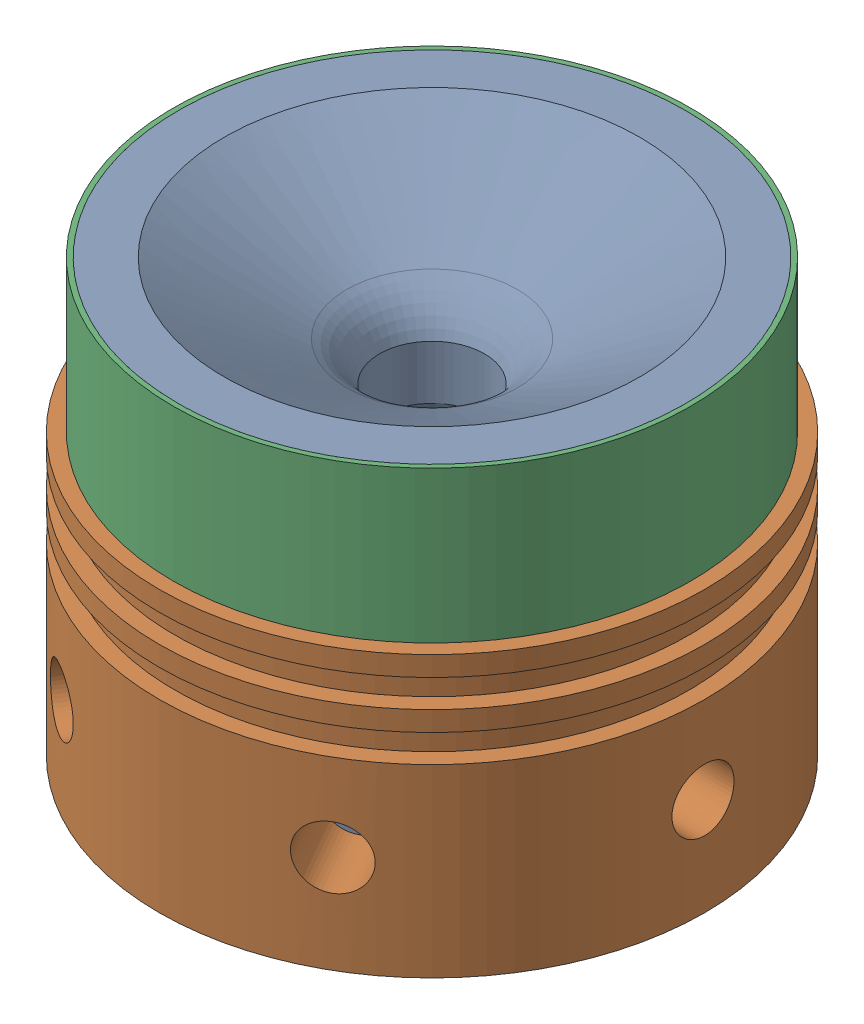
SolidWorks assembly 01_Nozzle_Assembly_COTS_GOW75BSTR23_V2.0, configuration Default. Lengths in mm.
Overall size (69.8 55.21 69.8).
3 component instances, 3 part files, 4 mates.
Components (placement in the parent):
- COTS_Nozzle_Modified_GOW75BSTR23_V1.0-1: COTS_Nozzle_Modified_GOW75BSTR23_V1.0 [Default] at (-2.3642 17.5716 -4.7601) size (64.95 55.21 64.95)
- Nozzle_Retainer_COTS_GOW75BSTR23_V2.0-1: Nozzle_Retainer_COTS_GOW75BSTR23_V2.0 [Default] at (-2.3642 -23.6207 -4.7601) size (69.8 35.83 69.8)
- Casting_Tube_Nozzle_Filler_GOW75BSTR23_V2.0-1: Casting_Tube_Nozzle_Filler_GOW75BSTR23_V2.0 [Default] at (-2.3642 17.0686 -4.7601) size (66.17 19.38 66.17)
Mates (geometry in assembly coordinates):
- Coincident1: coincident aligned: cylinder of COTS_Nozzle_Modified_GOW75BSTR23_V1.0-1 through (-2.3642 17.5716 -4.7601) axis (0 -1 0) radius 25.4; circle of Nozzle_Retainer_COTS_GOW75BSTR23_V2.0-1
- Coincident2: coincident anti-aligned: plane of COTS_Nozzle_Modified_GOW75BSTR23_V1.0-1 through (-27.7642 17.0686 -4.7601) normal (0 -1 0); plane of Nozzle_Retainer_COTS_GOW75BSTR23_V2.0-1 through (-37.2638 17.0686 -4.7601) normal (0 1 0)
- Concentric1: concentric aligned: cylinder of COTS_Nozzle_Modified_GOW75BSTR23_V1.0-1 through (-2.3642 17.5716 -4.7601) axis (0 -1 0) radius 32.4739; cylinder of Casting_Tube_Nozzle_Filler_GOW75BSTR23_V2.0-1 through (-2.3642 36.4488 -4.7601) axis (0 -1 0) radius 32.4612
- Coincident3: coincident anti-aligned: plane of Nozzle_Retainer_COTS_GOW75BSTR23_V2.0-1 through (-37.2638 17.0686 -4.7601) normal (0 1 0); plane of Casting_Tube_Nozzle_Filler_GOW75BSTR23_V2.0-1 through (-2.3642 17.0686 -4.7601) normal (0 -1 0)
